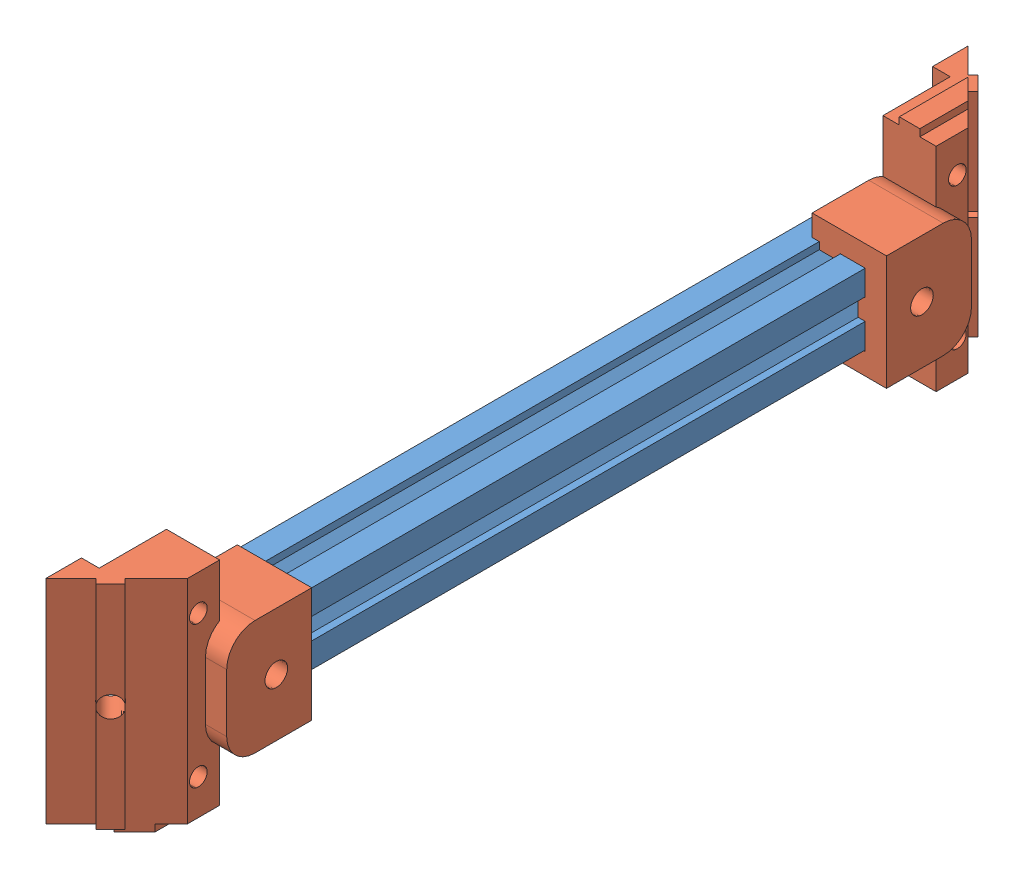
SolidWorks assembly WindowFixationMiddlesWithMakerBeam, configuration Default. Lengths in mm.
Overall size (35.21 42 131.54).
3 component instances, 2 part files, 6 mates.
Components (placement in the parent):
- Makerbeam50-1000mm-1: Makerbeam50-1000mm [100mm] at (29.5633 55.1843 28.8182) size (10 10 100)
- WindowFixationMiddle-1: WindowFixationMiddle [Default] at (24.5633 55.0843 143.3182) x (-0.707107 0 -0.707107) z (0 -1 0) size (19.74 30.05 41)
- WindowFixationMiddle-2: WindowFixationMiddle [Default] at (24.5633 55.0843 13.1973) x (-0.707107 0 0.707107) z (0 1 0) size (19.74 30.05 41)
Mates (geometry in assembly coordinates):
- Coïncidente2: coincident anti-aligned: plane of Makerbeam50-1000mm-1 through (29.5633 55.1843 128.8182) normal (0 0 1); plane of WindowFixationMiddle-1 through (34.5633 40.0843 128.8182) normal (0 0 -1)
- Coïncidente3: coincident anti-aligned: plane of Makerbeam50-1000mm-1 through (34.5633 60.1843 128.8182) normal (1 0 0); plane of WindowFixationMiddle-1 through (34.5633 46.9843 130.8182) normal (-1 0 0)
- Coïncidente4: coincident anti-aligned: plane of Makerbeam50-1000mm-1 through (31.0633 60.1843 128.8182) normal (0 1 0); plane of WindowFixationMiddle-1 through (31.0133 60.1843 118.8182) normal (0 -1 0)
- Coïncidente5: coincident aligned: plane of WindowFixationMiddle-1 through (24.5633 40.0843 128.8182) normal (-1 0 0); plane of WindowFixationMiddle-2 through (24.5633 70.0843 27.6973) normal (-1 0 0)
- Coïncidente6: coincident aligned: plane of WindowFixationMiddle-1 through (34.5633 63.1843 118.8182) normal (0 1 0); plane of WindowFixationMiddle-2 through (34.5633 63.1843 37.6973) normal (0 1 0)
- Parallèle2: parallel anti-aligned: plane of Makerbeam50-1000mm-1 through (29.5633 55.1843 28.8182) normal (0 0 -1); plane of WindowFixationMiddle-2 through (34.5633 70.0843 27.6973) normal (0 0 1)
